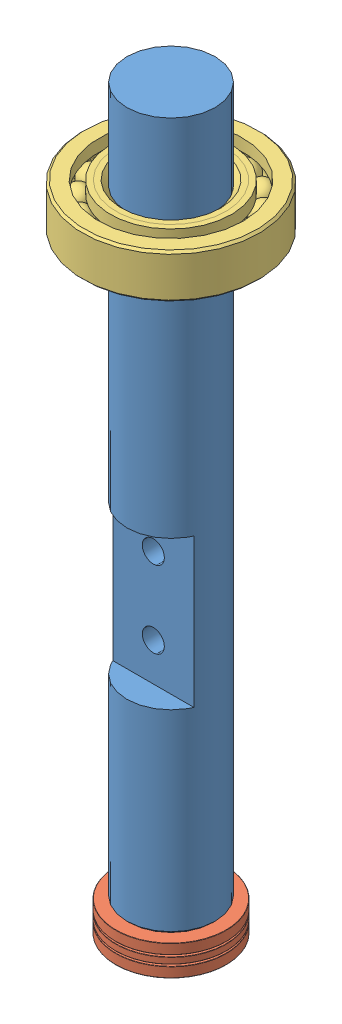
SolidWorks assembly Shoulder Assem Superdraft, configuration Default. Lengths in mm.
Overall size (61.43 211.89 61.43).
3 component instances, 3 part files, 3 mates.
Components (placement in the parent):
- Shoulder-Joint Superdraft-1: Shoulder-Joint Superdraft [Default] at (88.5966 40.6015 203.7568) size (25.4 210.82 25.4)
- 6655K190-1: 6655K190 [6655K19] at (88.5966 36.2581 203.7568) size (31.75 8.69 31.75)
- 6383K570-1: 6383K570 [6383K57] at (88.5966 213.1472 203.7568) x (0.971277 0 -0.23795) z (0 1 0) size (50.8 50.8 12.7)
Mates (geometry in assembly coordinates):
- Concentric2: concentric anti-aligned: cylinder of Shoulder-Joint Superdraft-1 through (88.5966 32.9815 203.7568) axis (0 1 0) radius 9.525; cylinder of 6655K190-1 through (88.5966 31.9147 203.7568) axis (0 -1 0) radius 9.525
- Coincident2: coincident anti-aligned: plane of Shoulder-Joint Superdraft-1 through (88.5966 40.6015 203.7568) normal (0 -1 0); plane of 6655K190-1 through (88.5966 40.6015 219.6318) normal (0 1 0)
- Concentric3: concentric anti-aligned: cylinder of Shoulder-Joint Superdraft-1 through (88.5966 243.8015 203.7568) axis (0 -1 0) radius 12.7; cylinder of 6383K570-1 through (88.5966 219.4972 203.7568) axis (0 1 0) radius 12.7
